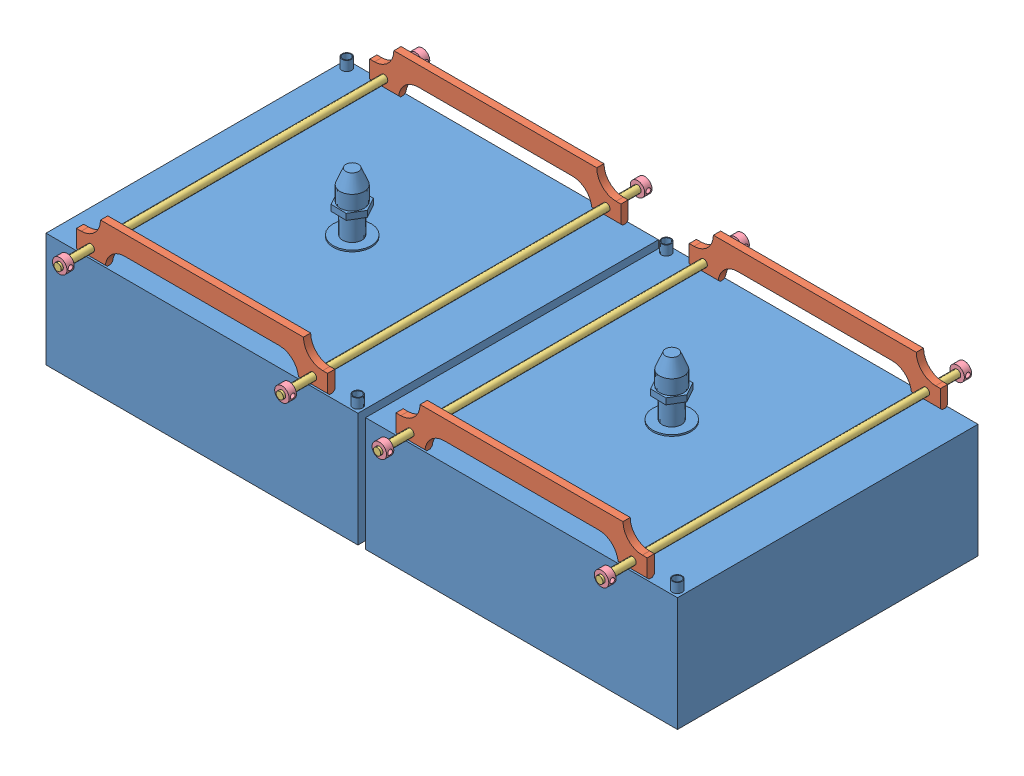
SolidWorks assembly 100-UltraSoundSource, configuration Upside-down. Lengths in mm.
Overall size (830 228.1 482.6).
19 component instances, 4 part files, 18 mates.
Components (placement in the parent):
- 101-UltraSoundBox-1: 101-UltraSoundBox [Default] at (-210 0 0) size (410 228.1 395)
- 101-UltraSoundBox-2: 101-UltraSoundBox [Default] at (210 0 0) size (410 228.1 395)
- 102-RodHolder-1: 102-RodHolder [Default] at (-210 0 197.5) size (330.2 50.8 9.53)
- 102-RodHolder-4: 102-RodHolder [Default] at (210 0 197.5) size (330.2 50.8 9.53)
- 103-RodYokes-1: 103-RodYokes [Default] at origin size (9.53 9.52 482.6)
- 103-RodYokes-3: 103-RodYokes [Default] at (292.1 0 0) size (9.53 9.52 482.6)
- 103-RodYokes-4: 103-RodYokes [Default] at (712.1 0 0) size (9.53 9.52 482.6)
- 103-RodYokes-2: 103-RodYokes [Default] at (420 0 0) size (9.53 9.52 482.6)
- 102-RodHolder-2: 102-RodHolder [Default] at (-210 0 -188.0212) size (330.2 50.8 9.53)
- 102-RodHolder-3: 102-RodHolder [Default] at (210 0 -188.0212) size (330.2 50.8 9.53)
- 004-ShaftCollar_Mcmaster-9943K18-1: 004-ShaftCollar_Mcmaster-9943K18 [Default] at origin size (19.05 19.05 9.53) (hidden)
- 004-ShaftCollar_Mcmaster-9943K18-2: 004-ShaftCollar_Mcmaster-9943K18 [Default] at (0 0 233.68) size (19.05 19.05 9.53)
- 004-ShaftCollar_Mcmaster-9943K18-6: 004-ShaftCollar_Mcmaster-9943K18 [Default] at (0 0 -233.68) size (19.05 19.05 9.53)
- 004-ShaftCollar_Mcmaster-9943K18-7: 004-ShaftCollar_Mcmaster-9943K18 [Default] at (292.1 0 -233.68) size (19.05 19.05 9.53)
- 004-ShaftCollar_Mcmaster-9943K18-3: 004-ShaftCollar_Mcmaster-9943K18 [Default] at (292.1 0 233.68) size (19.05 19.05 9.53)
- 004-ShaftCollar_Mcmaster-9943K18-5: 004-ShaftCollar_Mcmaster-9943K18 [Default] at (420.0652 0 233.68) size (19.05 19.05 9.53)
- 004-ShaftCollar_Mcmaster-9943K18-9: 004-ShaftCollar_Mcmaster-9943K18 [Default] at (420.0652 0 -233.68) size (19.05 19.05 9.53)
- 004-ShaftCollar_Mcmaster-9943K18-4: 004-ShaftCollar_Mcmaster-9943K18 [Default] at (712.1652 0 233.68) size (19.05 19.05 9.53)
- 004-ShaftCollar_Mcmaster-9943K18-8: 004-ShaftCollar_Mcmaster-9943K18 [Default] at (712.1652 0 -233.68) size (19.05 19.05 9.53)
Mates (geometry in assembly coordinates):
- Coincident1: coincident aligned: plane of 101-UltraSoundBox-1 through (-210 0 0) normal (0 0 1); plane of assembly through (0 0 0) normal (0 0 1)
- Coincident2: coincident aligned: plane of 101-UltraSoundBox-1 through (-210 0 0) normal (0 1 0); plane of assembly through (0 0 0) normal (0 1 0)
- Distance1: distance = 5 mm aligned: plane of 101-UltraSoundBox-1 through (-5 150 197.5) normal (1 0 0); plane of assembly through (0 0 0) normal (1 0 0)
- InPlace1: in place: plane of 101-UltraSoundBox-1 through (-415 0 197.5) normal (0 0 1); plane of 102-RodHolder-1; moOrthogonalPlaneRef_w of 101-UltraSoundBox-1; plane of 102-RodHolder-1; moOrthogonalPlaneRef_w of 101-UltraSoundBox-1; plane of 102-RodHolder-1
- Coincident4: coincident aligned: plane of 101-UltraSoundBox-1; plane of 102-RodHolder-1
- Coincident5: coincident aligned: moOrthogonalPlaneRef_w of 101-UltraSoundBox-1 through (-210 0 197.5) axis (0 1 0); plane of 102-RodHolder-1 through (-210 0 197.5) normal (0 1 0)
- Coincident6: coincident anti-aligned: moOrthogonalPlaneRef_w of 101-UltraSoundBox-1 through (-210 0 197.5) axis (-1 0 0); plane of 102-RodHolder-1 through (-210 0 197.5) normal (1 0 0)
- InPlace2: in place: unknown of ?
- Coincident7: coincident aligned: plane of 103-RodYokes-1; plane of assembly
- Coincident8: coincident aligned: plane of ? through (0 0 0) normal (0 1 0)
- Coincident9: coincident anti-aligned: plane of ? through (0 0 0) normal (1 0 0)
- Concentric1: concentric anti-aligned: cylinder of 102-RodHolder-1 through (-63.95 162.7 187.975) axis (0 0 1) radius 4.7625; cylinder of 103-RodYokes-3 through (-63.95 162.7 241.3) axis (0 0 -1) radius 4.7625
- Coincident10: coincident aligned: plane of 103-RodYokes-1 through (-356.05 162.7 241.3) normal (0 0 1); plane of 103-RodYokes-3 through (-63.95 162.7 241.3) normal (0 0 1)
- Parallel1: parallel aligned: plane of 103-RodYokes-1 through (0 0 0) normal (0 1 0); plane of 103-RodYokes-3 through (292.1 0 0) normal (0 1 0)
- InPlace3: in place: unknown of ?
- Coincident11: coincident aligned: plane of 004-ShaftCollar_Mcmaster-9943K18-1; plane of assembly
- Coincident12: coincident aligned: plane of ? through (0 0 0) normal (0 1 0)
- Coincident13: coincident anti-aligned: plane of ? through (0 0 0) normal (1 0 0)
